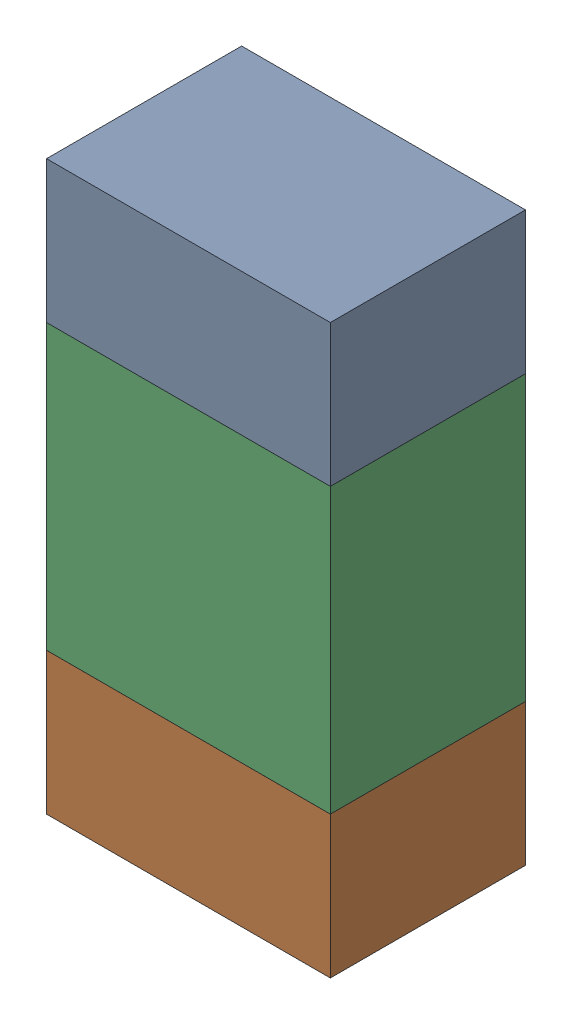
SolidWorks assembly R19, configuration ﾃﾞﾌｫﾙﾄ. Lengths in mm.
Overall size (0.8 1.6 0.55).
6 component instances, 2 part files, 0 mates.
Components (placement in the parent):
- 689261784-1: 689261784 [ﾃﾞﾌｫﾙﾄ] at (71.7501 53.8499 0) size (0.8 0.4 0.55)
  - Extruded_34-1: Extruded_34 [ﾃﾞﾌｫﾙﾄ] at origin size (0.8 0.4 0.55)
- 689261784-2: 689261784 [ﾃﾞﾌｫﾙﾄ] at (71.7501 52.6499 0) size (0.8 0.4 0.55)
  - Extruded_34-1: Extruded_34 [ﾃﾞﾌｫﾙﾄ] at origin size (0.8 0.4 0.55)
- 689261648-1: 689261648 [ﾃﾞﾌｫﾙﾄ] at (71.7501 53.25 0) size (0.8 0.8 0.55)
  - Extruded_33-1: Extruded_33 [ﾃﾞﾌｫﾙﾄ] at origin size (0.8 0.8 0.55)
